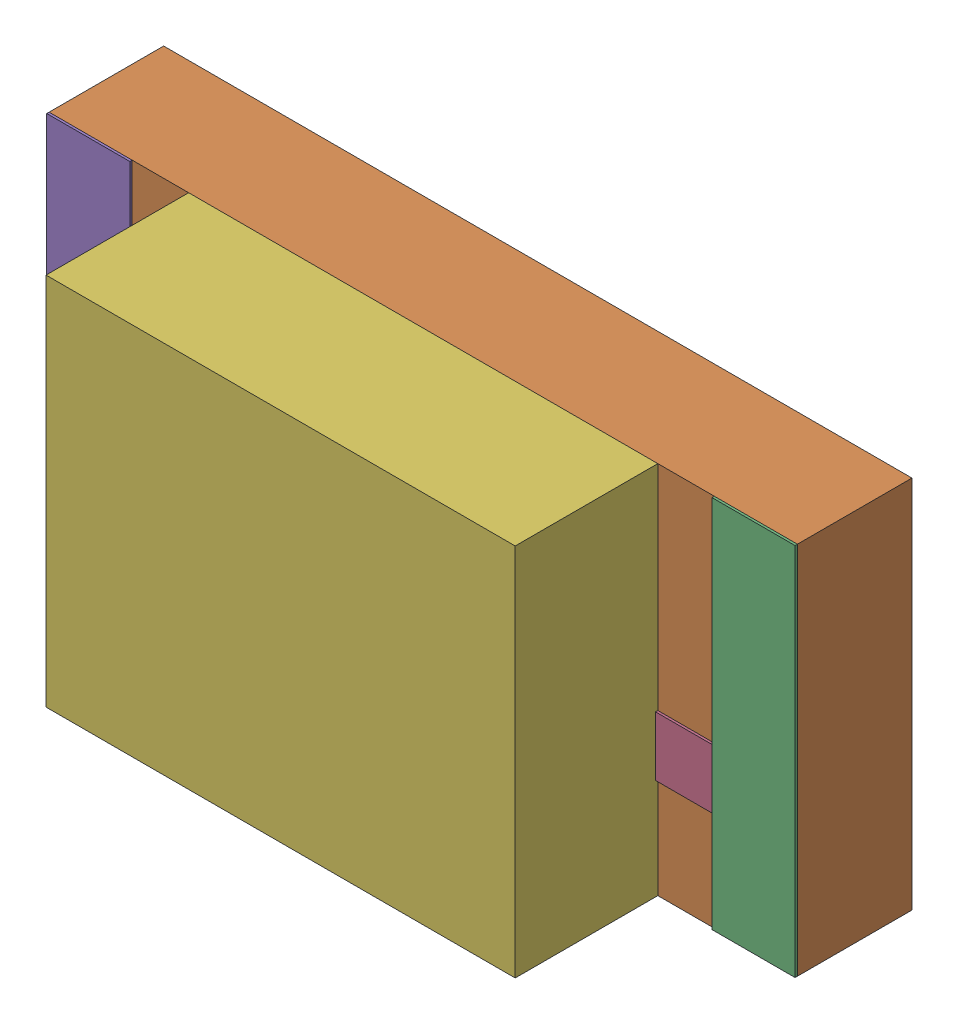
SolidWorks assembly SW3dPS-LED1206R_Open_CASCADE_STEP_translator_6.2_278.2, configuration Défaut. Lengths in mm.
Overall size (3.2 1.6 1.1).
12 component instances, 5 part files, 0 mates.
Components (placement in the parent):
- SW3dPS-LED1206R_352699472-1: SW3dPS-LED1206R_352699472 [Défaut] at (0.6096 0.0254 0.5027) size (0.65 0.76 0.01)
  - SW3dPS-LED1206R_Extruded3-1: SW3dPS-LED1206R_Extruded3 [Défaut] at origin size (0.65 0.76 0.01)
- SW3dPS-LED1206R_352697936-1: SW3dPS-LED1206R_352697936 [Défaut] at (1.524 0.0127 0.0127) size (3.2 1.6 0.49)
  - SW3dPS-LED1206R_Extruded1-1: SW3dPS-LED1206R_Extruded1 [Défaut] at origin size (3.2 1.6 0.49)
- SW3dPS-LED1206R_352697808-1: SW3dPS-LED1206R_352697808 [Défaut] at (2.9464 0.0127 0.5027) size (0.36 1.6 0.01)
  - SW3dPS-LED1206R_Extruded-1: SW3dPS-LED1206R_Extruded [Défaut] at origin size (0.36 1.6 0.01)
- SW3dPS-LED1206R_352698192-1: SW3dPS-LED1206R_352698192 [Défaut] at (2.1971 0.0254 0.5027) size (1.14 0.76 0.01)
  - SW3dPS-LED1206R_Extruded4-1: SW3dPS-LED1206R_Extruded4 [Défaut] at origin size (1.14 0.76 0.01)
- SW3dPS-LED1206R_352697808-2: SW3dPS-LED1206R_352697808 [Défaut] at (0.1016 0.0127 0.5027) size (0.36 1.6 0.01)
  - SW3dPS-LED1206R_Extruded-1: SW3dPS-LED1206R_Extruded [Défaut] at origin size (0.36 1.6 0.01)
- SW3dPS-LED1206R_352701008-1: SW3dPS-LED1206R_352701008 [Défaut] at (1.524 0.0127 0.5027) size (2.01 1.6 0.61)
  - SW3dPS-LED1206R_Extruded2-1: SW3dPS-LED1206R_Extruded2 [Défaut] at origin size (2.01 1.6 0.61)
